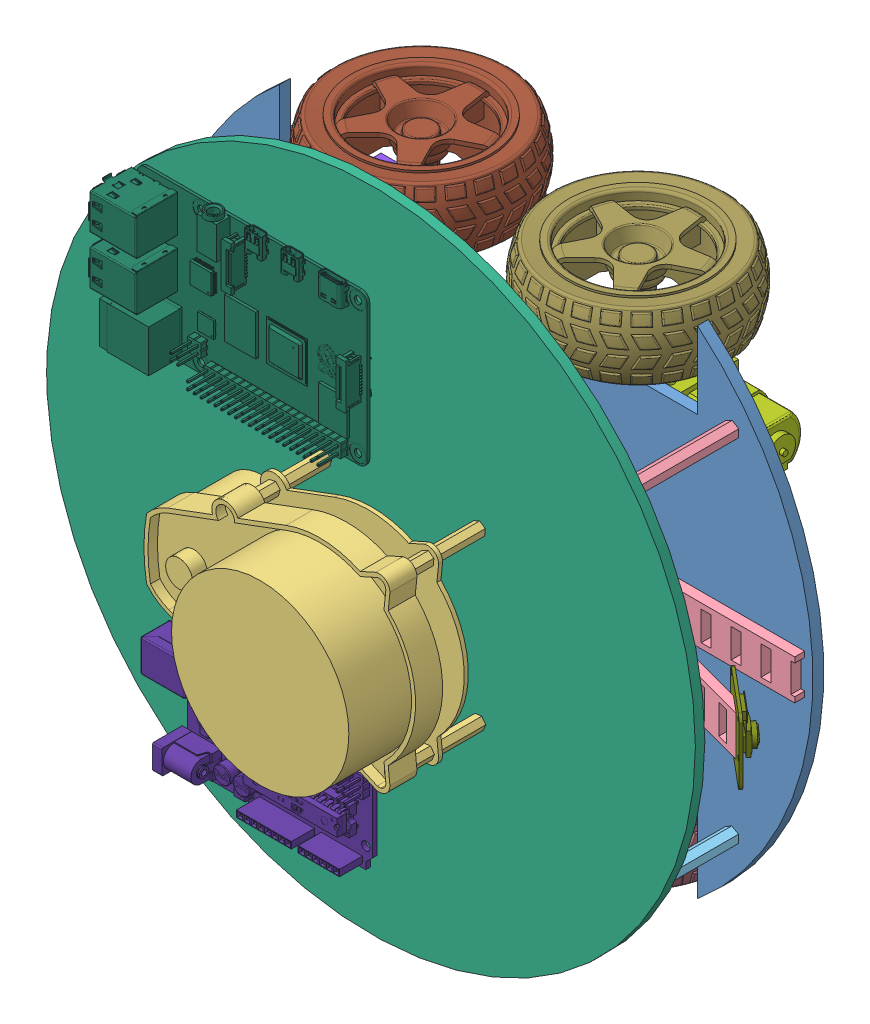
SolidWorks assembly agv, configuration Default. Lengths in mm.
Overall size (254.84 240 154.37).
23 component instances, 22 part files, 0 mates.
Components (placement in the parent):
- agv.step-1: agv.step [Default] at origin size (254.84 240 154.37)
  - base_link.step-1: base_link.step [Default] at (0.7213 0 45.6092) size (240 183.63 4)
  - spacerBL.step-1: spacerBL.step [Default] at (0.7213 0 45.6092) size (5.06 5.77 40)
  - spacerBR.step-1: spacerBR.step [Default] at (0.7213 0 45.6092) size (5.06 5.77 40)
  - spacerFL.step-1: spacerFL.step [Default] at (0.7213 0 45.6092) size (5.06 5.77 40)
  - spacerFR.step-1: spacerFR.step [Default] at (0.7213 0 45.6092) size (5.06 5.77 40)
  - top.step-1: top.step [Default] at (0.7213 0 39.6092) size (240 240 3.5)
  - motor v1.step-1: motor v1.step [Default] at (57.4213 52.05 34.4592) x (0 0 1) z (-1 0 0) size (22.3 37 70.8)
  - motorBL.step-1: motorBL.step [Default] at (-55.9787 53.75 34.4592) x (0 0 1) z (1 0 0) size (22.3 37 70.8)
  - motorFR.step-1: motorFR.step [Default] at (57.4213 -53.75 34.4592) x (0 0 1) z (-1 0 0) size (22.3 37 70.8)
  - motorBR.step-1: motorBR.step [Default] at (-55.9787 -52.05 34.4592) x (0 0 1) z (1 0 0) size (22.3 37 70.8)
  - BWL.step-1: BWL.step [Default] at (-39.3587 93.4 34.4592) x (1 0 0) z (0 1 0) size (73.43 73.43 30)
  - FWL.step-1: FWL.step [Default] at (40.8013 93.4 34.4592) x (1 0 0) z (0 1 0) size (73.43 73.43 30)
  - FWR.step-1: FWR.step [Default] at (40.8013 -93.4 34.4592) x (1 0 0) z (0 -1 0) size (73.43 73.43 30)
  - BWR.step-1: BWR.step [Default] at (-39.3587 -93.4 34.4592) x (1 0 0) z (0 -1 0) size (73.43 73.43 30)
  - Raspberry_Pi.step-1: Raspberry_Pi.step [Default] at (3.2213 88 97.0392) x (-1 0 0) z (0 0 1) size (87.94 57.9 19.63)
  - pi_cam.step-1: pi_cam.step [Default] at (121.8433 0 79.6338) x (0.642788 0 -0.766044) z (0.766044 0 0.642788) size (6.45 24 25)
  - Arduino Uno v1.step-1: Arduino Uno v1.step [Default] at (-63.5687 -96.67 96.7592) x (0 -1 0) z (-1 0 0) size (53.34 15.25 74.93)
  - mi powerbank 2 v1.step-1: mi powerbank 2 v1.step [Default] at (-34.2787 0 56.6592) x (0 -1 0) z (0 0 -1) size (71 130 14.1)
  - L298N .step-1: L298N .step [Default] at (-28.1416 13.6094 62.3183) x (0 -1 0) z (1 0 0) size (30.33 14.63 32.09)
  - battery.step-1: battery.step [Default] at (-70.8412 0 37.1092) x (0 -1 0) z (0 0 1) size (26 48.25 17)
  - Lidar.step-1: Lidar.step [Default] at (18.7213 -1 120.1092) size (101.5 71 59)
  - cam_holder.step-1: cam_holder.step [Default] at (3.0373 -27.179 39.7523) size (85.84 14.74 32.71)
